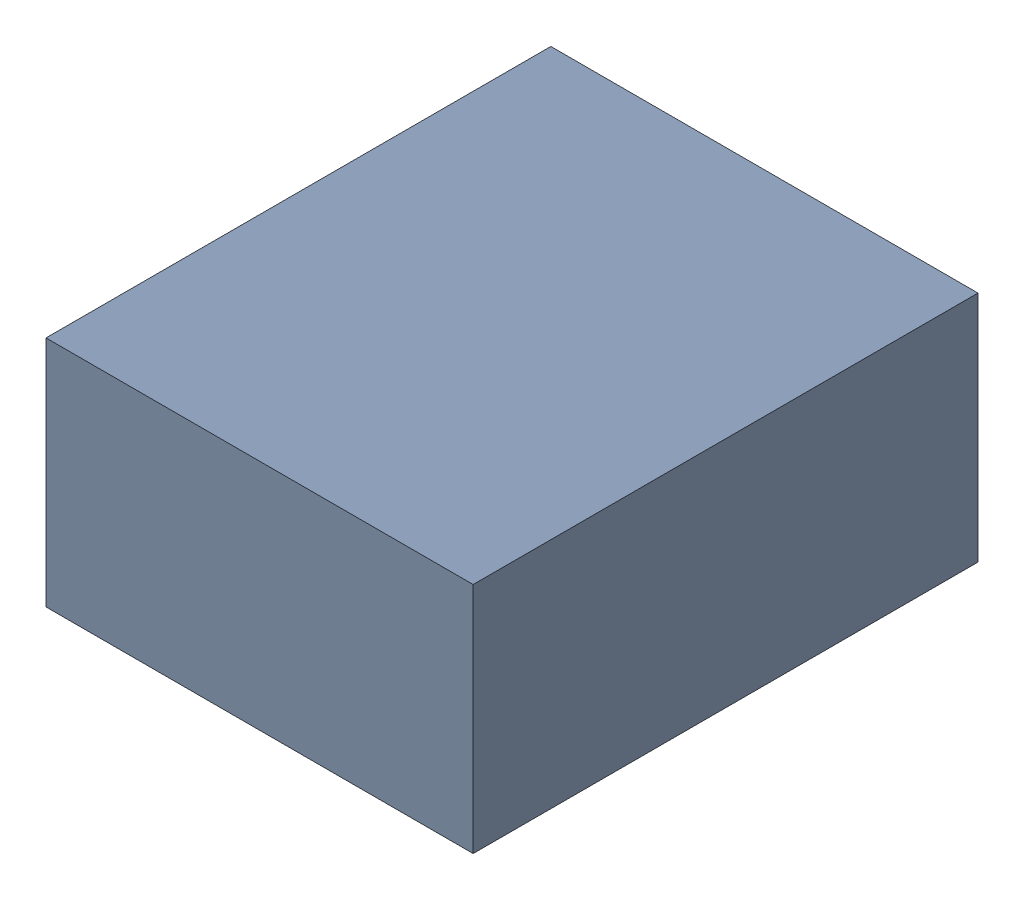
SolidWorks assembly C29_TDA4, configuration Standard. Lengths in mm.
Overall size (1.1 0.6 1.3).
2 component instances, 1 part files, 0 mates.
Components (placement in the parent):
- 885542240-1: 885542240 [Standard] at (0.38 -58.09 0) size (1.1 0.6 1.3)
  - Extruded_28-1: Extruded_28 [Standard] at origin size (1.1 0.6 1.3)
